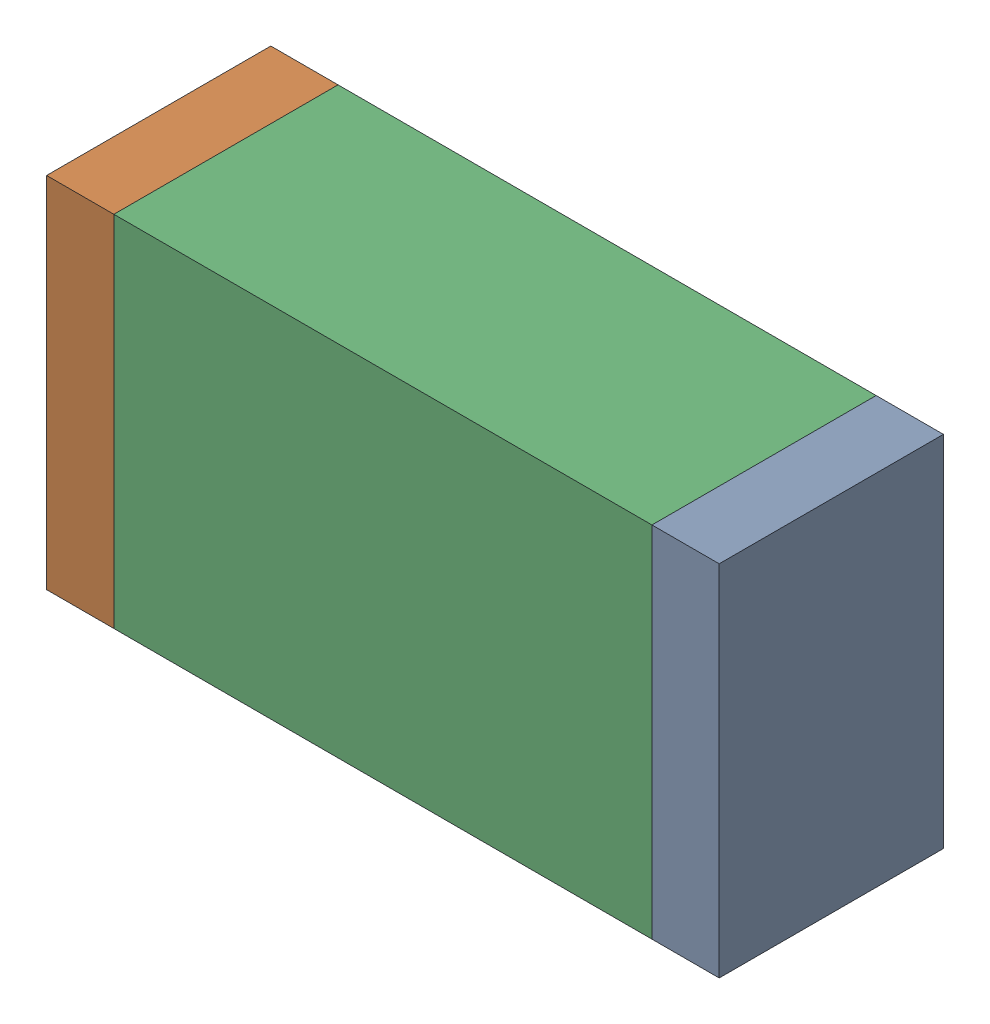
SolidWorks assembly D2, configuration Default. Lengths in mm.
Overall size (1.5 0.8 0.5).
6 component instances, 2 part files, 0 mates.
Components (placement in the parent):
- 836752496-1: 836752496 [Default] at (125.975 7.85 0) size (0.15 0.8 0.5)
  - Extruded_2-1: Extruded_2 [Default] at origin size (0.15 0.8 0.5)
- 836752496-2: 836752496 [Default] at (124.625 7.85 0) size (0.15 0.8 0.5)
  - Extruded_2-1: Extruded_2 [Default] at origin size (0.15 0.8 0.5)
- 836752368-1: 836752368 [Default] at (125.3 7.85 0) size (1.2 0.8 0.5)
  - Extruded-1: Extruded [Default] at origin size (1.2 0.8 0.5)
